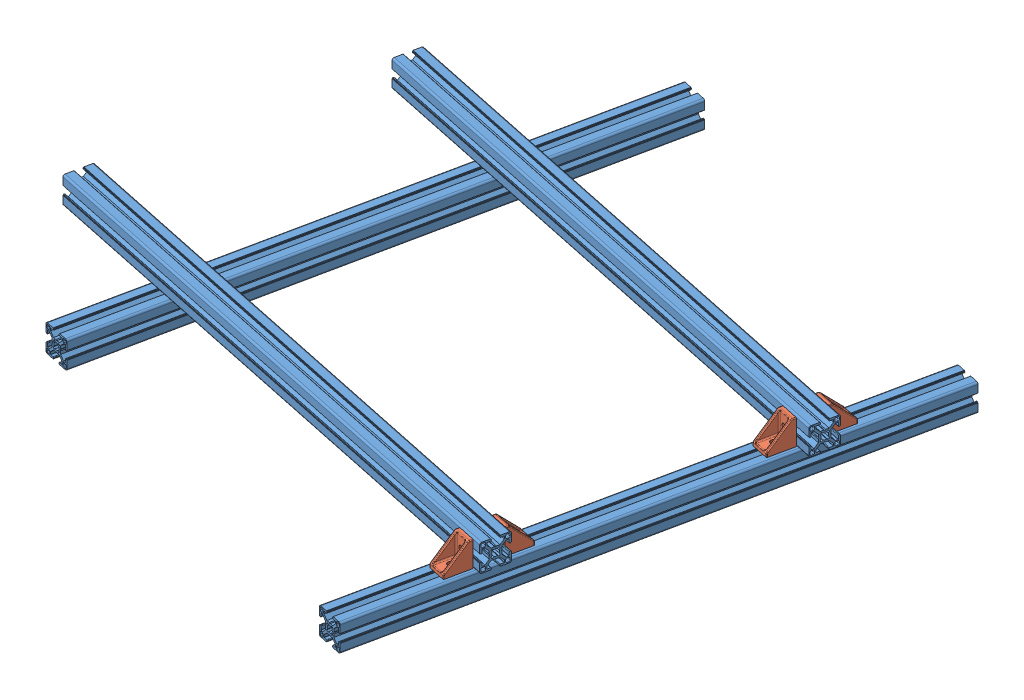
SolidWorks assembly Assem3, configuration Default. Lengths in mm.
Overall size (679.78 60 714.11).
8 component instances, 2 part files, 20 mates.
Components (placement in the parent):
- 600mm Aluminium Profile-4: 600mm Aluminium Profile [Default] at (664.6978 -709.8547 222.281) x (-0.978713 0 -0.205235) z (0.205235 0 -0.978713) size (30 30 600)
- 600mm Aluminium Profile-5: 600mm Aluminium Profile [Default] at (2.6801 -679.8547 550.015) x (-0.205235 0 0.978713) z (-0.978713 0 -0.205235) size (30 30 600)
- Aluminium profile 30mm corner bracket slim-2: Aluminium profile 30mm corner bracket slim [Default] at (573.6617 -695.8919 705.6204) x (0.205235 0 -0.978713) z (0 1 0) size (29.8 20 29.8)
- Aluminium profile 30mm corner bracket slim-3: Aluminium profile 30mm corner bracket slim [Default] at (568.498 -695.8919 632.7954) x (-0.205235 0 0.978713) z (0 1 0) size (29.8 20 29.8)
- 600mm Aluminium Profile-8: 600mm Aluminium Profile [Default] at (116.418 -709.8547 688.7866) x (0.978713 0 0.205235) z (-0.205235 0 0.978713) size (30 30 600)
- Aluminium profile 30mm corner bracket slim-8: Aluminium profile 30mm corner bracket slim [Default] at (636.0442 -695.8919 408.1347) x (0.205235 0 -0.978713) z (0 1 0) size (29.8 20 29.8)
- Aluminium profile 30mm corner bracket slim-10: Aluminium profile 30mm corner bracket slim [Default] at (630.8805 -695.8919 335.3097) x (-0.205235 0 0.978713) z (0 1 0) size (29.8 20 29.8)
- 600mm Aluminium Profile-10: 600mm Aluminium Profile [Default] at (73.5249 -679.8547 254.3038) x (-0.205235 0 0.978713) z (-0.978713 0 -0.205235) size (30 30 600)
Mates (geometry in assembly coordinates):
- Coincident6: coincident anti-aligned: plane of 600mm Aluminium Profile-4 through (546.2056 -694.8547 810.4835) normal (0 1 0); plane of 600mm Aluminium Profile-5 through (588.9328 -694.8547 677.8049) normal (0 -1 0)
- Coincident9: coincident anti-aligned: plane of 600mm Aluminium Profile-4 through (536.9078 -694.8547 808.5338) normal (0 1 0); plane of 600mm Aluminium Profile-5 through (588.9328 -694.8547 677.8049) normal (0 -1 0)
- Perpendicular9: perpendicular: line of 600mm Aluminium Profile-5 through (592.9862 -692.8547 658.4754) axis (-0.978713 0 -0.205235); line of 600mm Aluminium Profile-4 through (526.876 -696.8547 806.4301) axis (0.205235 0 -0.978713)
- Coincident12: coincident: plane of 600mm Aluminium Profile-4 through (537.5929 -695.5547 808.6774) normal (0.978713 0 0.205235); line of Aluminium profile 30mm corner bracket slim-2 through (563.2213 -696.3547 686.4623) axis (-0.205235 0 0.978713)
- Coincident13: coincident anti-aligned: plane of 600mm Aluminium Profile-4 through (536.9078 -694.8547 808.5338) normal (0 1 0); plane of Aluminium profile 30mm corner bracket slim-2 through (552.3352 -694.8547 709.8715) normal (0 -1 0)
- Coincident14: coincident anti-aligned: plane of 600mm Aluminium Profile-5 through (586.8292 -666.8547 687.8367) normal (-0.205235 0 0.978713); plane of Aluminium profile 30mm corner bracket slim-2 through (558.2142 -694.8547 681.8362) normal (0.205235 0 -0.978713)
- Coincident15: coincident anti-aligned: plane of 600mm Aluminium Profile-4 through (537.5929 -695.5547 808.6774) normal (0.978713 0 0.205235); plane of Aluminium profile 30mm corner bracket slim-3 through (570.7535 -696.6547 650.5436) normal (-0.978713 0 -0.205235)
- Coincident16: coincident anti-aligned: plane of 600mm Aluminium Profile-4 through (546.2056 -694.8547 810.4835) normal (0 1 0); plane of Aluminium profile 30mm corner bracket slim-3 through (589.8245 -694.8547 628.5442) normal (0 -1 0)
- Coincident17: coincident anti-aligned: plane of 600mm Aluminium Profile-5 through (592.9862 -666.8547 658.4754) normal (0.205235 0 -0.978713); plane of Aluminium profile 30mm corner bracket slim-3 through (583.9455 -694.8547 656.5795) normal (-0.205235 0 0.978713)
- Coincident18: coincident anti-aligned: plane of Aluminium profile 30mm corner bracket slim-5 through (367.0447 -4.8552 1191.3179) normal (0.978713 0 0.205235); plane of 600mm Aluminium Profile-7 through (480.3708 23.1448 650.8953) normal (-0.978713 0 -0.205235)
- Coincident22: coincident anti-aligned: plane of Aluminium profile 30mm corner bracket slim-10 through (646.328 -694.8547 359.0938) normal (-0.205235 0 0.978713); plane of 600mm Aluminium Profile-10 through (663.831 -666.8547 362.7642) normal (0.205235 0 -0.978713)
- Coincident24: coincident anti-aligned: plane of Aluminium profile 30mm corner bracket slim-8 through (620.5967 -694.8547 384.3505) normal (0.205235 0 -0.978713); plane of 600mm Aluminium Profile-10 through (657.674 -666.8547 392.1256) normal (-0.205235 0 0.978713)
- Coincident29: coincident aligned: plane of Aluminium profile 30mm corner bracket slim-8 through (614.7177 -694.8547 412.3858) normal (0 -1 0); plane of 600mm Aluminium Profile-10 through (659.7776 -694.8547 382.0938) normal (0 -1 0)
- Coincident30: coincident aligned: plane of Aluminium profile 30mm corner bracket slim-10 through (652.207 -694.8547 331.0585) normal (0 -1 0); plane of 600mm Aluminium Profile-10 through (661.7274 -694.8547 372.796) normal (0 -1 0)
- Coincident31: coincident aligned: plane of Aluminium profile 30mm corner bracket slim-8 through (619.9644 -669.8547 387.3658) normal (-0.978713 0 -0.205235); plane of Aluminium profile 30mm corner bracket slim-10 through (627.386 -669.8547 351.9739) normal (-0.978713 0 -0.205235)
- Coincident32: coincident anti-aligned: plane of 600mm Aluminium Profile-4 through (537.5929 -695.5547 808.6774) normal (0.978713 0 0.205235); plane of Aluminium profile 30mm corner bracket slim-10 through (637.3334 -696.6547 333.0414) normal (-0.978713 0 -0.205235)
- Coincident33: coincident anti-aligned: plane of 600mm Aluminium Profile-4 through (546.2056 -694.8547 810.4835) normal (0 1 0); plane of Aluminium profile 30mm corner bracket slim-10 through (652.207 -694.8547 331.0585) normal (0 -1 0)
- Coincident34: coincident anti-aligned: plane of 600mm Aluminium Profile-8 through (234.9102 -694.8547 100.5842) normal (0 1 0); plane of 600mm Aluminium Profile-10 through (661.7274 -694.8547 372.796) normal (0 -1 0)
- Parallel8: parallel anti-aligned: line of 600mm Aluminium Profile-4 through (556.2374 -696.8547 812.5872) axis (0.205235 0 -0.978713); line of 600mm Aluminium Profile-8 through (252.2824 -694.8547 104.2271) axis (-0.205235 0 0.978713)
- Parallel9: parallel aligned: line of 600mm Aluminium Profile-5 through (592.5758 -664.8547 660.4328) axis (-0.978713 0 -0.205235); line of 600mm Aluminium Profile-10 through (658.0844 -664.8547 390.1682) axis (-0.978713 0 -0.205235)
